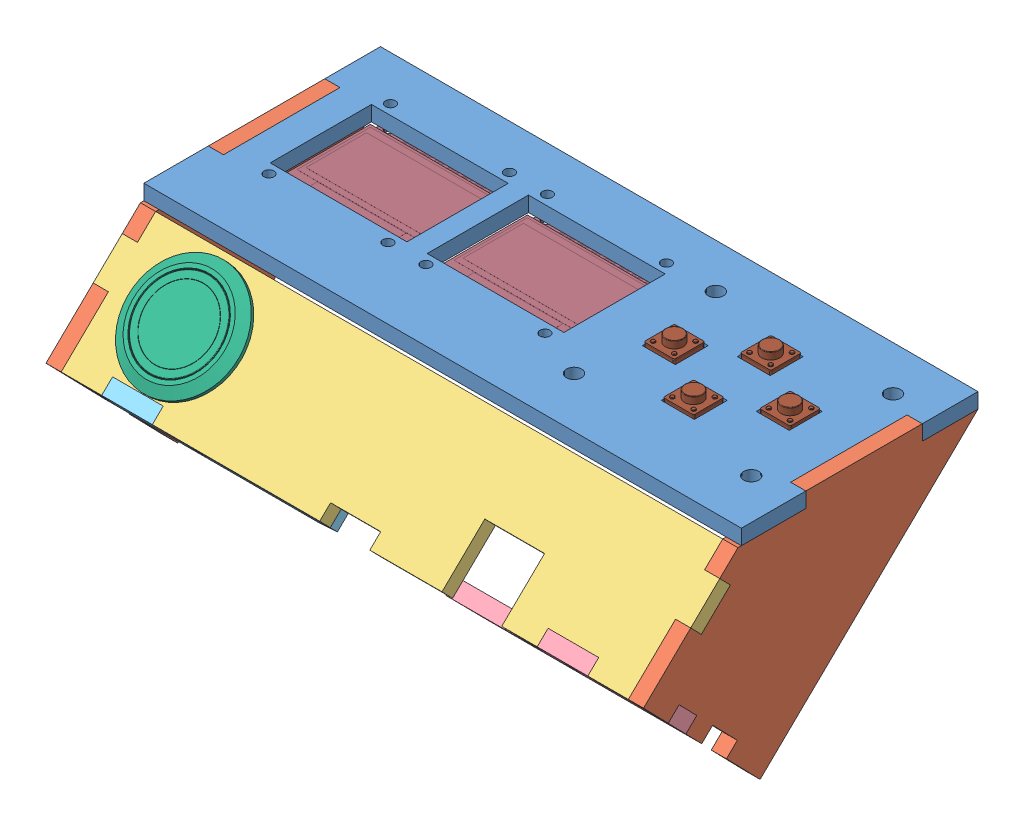
SolidWorks assembly screen, configuration Default. Lengths in mm.
Overall size (118 69.49 69.53).
64 component instances, 18 part files, 28 mates.
Components (placement in the parent):
- screen_face-1: screen_face [Default] at (-28.2935 6.7391 9.7495) size (118 3 46.73)
- screen_side-1: screen_side [Default] at (31.1583 3998.6355 -1824.0898) x (0 -0.717159 -0.69691) z (0 -0.69691 0.717159) size (33.04 3 60)
- screen_front-1: screen_front [Default] at (-1182.2499 1690.6865 -1707.8702) x (1 0 0) z (0 -0.69691 0.717159) size (118 3 26)
- screen_side-2: screen_side [Default] at (-83.8417 3998.6355 -1824.0898) x (0 -0.717159 -0.69691) z (0 -0.69691 0.717159) size (33.04 3 60)
- screen_bottom_right-1: screen_bottom_right [Default] at (-14.7308 -14.1194 45.2949) x (-1 0 0) z (0 -0.717159 -0.69691) size (47.26 3 16.5)
- screen_bottom_left-1: screen_bottom_left [Default] at (-25.4617 -14.6064 40.6384) x (1 0 0) z (0 -0.717159 -0.69691) size (54.05 3 16.5)
- power_switch-1: power_switch [Défaut] at (-65.8417 -14.1024 25.7899) x (0.866025 -0.348455 0.358579) z (0 0.717159 0.69691) size (22 25.2 38.75)
- pcb_buttons-1: pcb_buttons [Default] at (7.7205 6.7731 4.0037) x (-1 0 0) z (0 -1 0) size (43.5 35.88 10.33)
  - Dip_buttons-1: Dip_buttons [Default] at origin size (43.5 35.88 0.32)
  - Capacitor 0603_buttons-1: Capacitor 0603_buttons [Default] at (-1.2809 -0.2801 0.352) x (0 -1 0) z (-1 0 0) size (1.6 0.86 0.86)
  - Capacitor 0603_buttons-2: Capacitor 0603_buttons [Default] at (-3.1859 -0.2507 0.352) x (0 -1 0) z (-1 0 0) size (1.6 0.86 0.86)
  - Capacitor 0603_buttons-3: Capacitor 0603_buttons [Default] at (1.5918 -0.2507 0.352) x (0 -1 0) z (-1 0 0) size (1.6 0.86 0.86)
  - Capacitor 0603_buttons-4: Capacitor 0603_buttons [Default] at (3.4811 -0.2948 0.352) x (0 -1 0) z (-1 0 0) size (1.6 0.86 0.86)
  - Hole_Hole_buttons-1: Hole_Hole_buttons [Default] at (-17.462 13.97 0.322)
  - Hole_Hole_buttons-2: Hole_Hole_buttons [Default] at (17.462 -13.97 0.322)
  - Hole_Hole_buttons-3: Hole_Hole_buttons [Default] at (17.462 13.97 0.322)
  - Hole_Hole_buttons-4: Hole_Hole_buttons [Default] at (-17.462 -13.97 0.322)
  - S4B-ZR-SM4A-TF_buttons-1: S4B-ZR-SM4A-TF_buttons [Default] at (11.146 7.143 0.322) x (0.707107 0.707107 0) z (0.707107 -0.707107 0) size (9 3.7 6.5)
  - 4xRes_0402_buttons-1: 4xRes_0402_buttons [По умолчанию] at (-6.8859 7.489 0.322) x (0 -1 0) z (-1 0 0) size (2 0.37 1)
  - 4xRes_0402_buttons-2: 4xRes_0402_buttons [По умолчанию] at (-6.8317 -7.7471 0.322) x (0 -1 0) z (-1 0 0) size (2 0.37 1)
  - Tactile switch 6x6x5mm_buttons-1: Tactile switch 6x6x5mm_buttons [Valor predeterminado] at (0 7.62 0) x (1 0 0) z (0 1 0) size (6.03 8.52 7.74)
  - Tactile switch 6x6x5mm_buttons-2: Tactile switch 6x6x5mm_buttons [Valor predeterminado] at (-11.43 0 0) x (0 -1 0) z (1 0 0) size (6.03 8.52 7.74)
  - Tactile switch 6x6x5mm_buttons-3: Tactile switch 6x6x5mm_buttons [Valor predeterminado] at (0 -7.62 0) x (1 0 0) z (0 1 0) size (6.03 8.52 7.74)
  - Tactile switch 6x6x5mm_buttons_CUT-1: Tactile switch 6x6x5mm_buttons_CUT [Valor predeterminado] at (11.43 0 0) x (0 -1 0) z (1 0 0) size (6.03 8.52 7.74)
  - B8B-PH-SM4_buttons-1: B8B-PH-SM4_buttons [Default] at (11.938 -9.982 0.322) x (1 0 0) z (0 -1 0) size (15 5 5.2)
  - Via_Via_buttons-1: Via_Via_buttons [Default] at (4.45 0.635 0.322)
  - Via_Via_buttons-2: Via_Via_buttons [Default] at (-7.366 8.89 0.322)
  - Via_Via_buttons-3: Via_Via_buttons [Default] at (3.43 -2.148 0.322)
  - Via_Via_buttons-4: Via_Via_buttons [Default] at (3.43 6.223 0.322)
  - Via_Via_buttons-5: Via_Via_buttons [Default] at (-9.944 -0.354 0.322)
  - Via_Via_buttons-6: Via_Via_buttons [Default] at (-0.313 -0.354 0.322)
  - Via_Via_buttons-7: Via_Via_buttons [Default] at (0.398 6.223 0.322)
  - Via_Via_buttons-8: Via_Via_buttons [Default] at (-5.377 -1.065 0.322)
  - Via_Via_buttons-9: Via_Via_buttons [Default] at (17.196 -2.25 0.322)
  - Via_Via_buttons-10: Via_Via_buttons [Default] at (1.666 -8.001 0.322)
  - Via_Via_buttons-11: Via_Via_buttons [Default] at (-5.645 6.807 0.322)
- display-1: display [Default] at (-18.4635 -4.217 -13.179) x (1 0 0.00008) z (-0.00008 0.000036 1) size (27.3 3.37 27.3)
  - oled_display-1: oled_display [Default] at (-42.7279 10.3551 15.964) size (27.3 2.57 27.3)
  - Capacitor 0603_motor-1: Capacitor 0603_motor [Default] at (-47.8827 7.6343 13.4548) x (0 0 -1) z (1 0 0) size (1.6 0.86 0.86)
  - Resistor 0603_motor-1: Resistor 0603_motor [Default] at (-45.8966 7.9986 13.4983) x (0 0 -1) z (1 0 0) size (1.6 0.51 0.86)
  - Resistor 0603_motor-2: Resistor 0603_motor [Default] at (-43.8966 7.9986 13.4983) x (0 0 -1) z (1 0 0) size (1.6 0.51 0.86)
  - Capacitor 0603_motor-2: Capacitor 0603_motor [Default] at (-49.8827 7.6343 13.4548) x (0 0 -1) z (1 0 0) size (1.6 0.86 0.86)
  - Capacitor 0603_motor-3: Capacitor 0603_motor [Default] at (-51.8827 7.6343 13.4548) x (0 0 -1) z (1 0 0) size (1.6 0.86 0.86)
  - Capacitor 0603_motor-4: Capacitor 0603_motor [Default] at (-53.8827 7.6343 13.4548) x (0 0 -1) z (1 0 0) size (1.6 0.86 0.86)
  - Capacitor 0603_motor-5: Capacitor 0603_motor [Default] at (-41.8827 7.6343 13.4548) x (0 0 -1) z (1 0 0) size (1.6 0.86 0.86)
  - Capacitor 0603_motor-6: Capacitor 0603_motor [Default] at (-37.8827 7.6343 13.4548) x (0 0 -1) z (1 0 0) size (1.6 0.86 0.86)
  - Resistor 0603_motor-3: Resistor 0603_motor [Default] at (-39.8966 7.9986 13.4983) x (0 0 -1) z (1 0 0) size (1.6 0.51 0.86)
  - Resistor 0603_motor-4: Resistor 0603_motor [Default] at (-35.8966 7.9986 13.4983) x (0 0 -1) z (1 0 0) size (1.6 0.51 0.86)
  - Capacitor 0603_motor-7: Capacitor 0603_motor [Default] at (-33.8827 7.6343 13.4548) x (0 0 -1) z (1 0 0) size (1.6 0.86 0.86)
  - Capacitor 0603_motor-8: Capacitor 0603_motor [Default] at (-31.8827 7.6343 13.4548) x (0 0 -1) z (1 0 0) size (1.6 0.86 0.86)
- display-2: display [Default] at (12.5365 -4.217 -13.179) x (1 0 0.00008) z (-0.00008 0.000036 1) size (27.3 3.37 27.3)
  - oled_display-1: oled_display [Default] at (-42.7279 10.3551 15.964) size (27.3 2.57 27.3)
  - Capacitor 0603_motor-1: Capacitor 0603_motor [Default] at (-47.8827 7.6343 13.4548) x (0 0 -1) z (1 0 0) size (1.6 0.86 0.86)
  - Resistor 0603_motor-1: Resistor 0603_motor [Default] at (-45.8966 7.9986 13.4983) x (0 0 -1) z (1 0 0) size (1.6 0.51 0.86)
  - Resistor 0603_motor-2: Resistor 0603_motor [Default] at (-43.8966 7.9986 13.4983) x (0 0 -1) z (1 0 0) size (1.6 0.51 0.86)
  - Capacitor 0603_motor-2: Capacitor 0603_motor [Default] at (-49.8827 7.6343 13.4548) x (0 0 -1) z (1 0 0) size (1.6 0.86 0.86)
  - Capacitor 0603_motor-3: Capacitor 0603_motor [Default] at (-51.8827 7.6343 13.4548) x (0 0 -1) z (1 0 0) size (1.6 0.86 0.86)
  - Capacitor 0603_motor-4: Capacitor 0603_motor [Default] at (-53.8827 7.6343 13.4548) x (0 0 -1) z (1 0 0) size (1.6 0.86 0.86)
  - Capacitor 0603_motor-5: Capacitor 0603_motor [Default] at (-41.8827 7.6343 13.4548) x (0 0 -1) z (1 0 0) size (1.6 0.86 0.86)
  - Capacitor 0603_motor-6: Capacitor 0603_motor [Default] at (-37.8827 7.6343 13.4548) x (0 0 -1) z (1 0 0) size (1.6 0.86 0.86)
  - Resistor 0603_motor-3: Resistor 0603_motor [Default] at (-39.8966 7.9986 13.4983) x (0 0 -1) z (1 0 0) size (1.6 0.51 0.86)
  - Resistor 0603_motor-4: Resistor 0603_motor [Default] at (-35.8966 7.9986 13.4983) x (0 0 -1) z (1 0 0) size (1.6 0.51 0.86)
  - Capacitor 0603_motor-7: Capacitor 0603_motor [Default] at (-33.8827 7.6343 13.4548) x (0 0 -1) z (1 0 0) size (1.6 0.86 0.86)
  - Capacitor 0603_motor-8: Capacitor 0603_motor [Default] at (-31.8827 7.6343 13.4548) x (0 0 -1) z (1 0 0) size (1.6 0.86 0.86)
Mates (geometry in assembly coordinates):
- Coincident7: coincident anti-aligned: plane of screen_face-1 through (31.1583 9.7391 -7.0991) normal (1 0 0); plane of screen_side-1 through (31.1583 3998.6355 -1824.0898) normal (-1 0 0)
- Coincident8: coincident anti-aligned: plane of screen_face-1 through (31.1583 9.7391 15.9009) normal (0 0 -1); plane of screen_side-1 through (34.1583 6.7391 15.9009) normal (0 0 1)
- Coincident9: coincident aligned: plane of screen_side-1 through (34.1583 -2.3207 38.6333) normal (0 0.717159 0.69691); plane of screen_front-1 through (-1182.2499 1692.838 -1705.7795) normal (0 0.717159 0.69691)
- Coincident10: coincident anti-aligned: plane of screen_side-1 through (31.1583 3998.6355 -1824.0898) normal (-1 0 0); plane of screen_front-1 through (31.1583 6.7391 29.3102) normal (1 0 0)
- Coincident11: coincident aligned: plane of screen_face-1 through (-28.2935 9.7391 9.7495) normal (0 1 0); plane of screen_side-1 through (34.1583 9.7391 15.9009) normal (0 1 0)
- Coincident12: coincident anti-aligned: plane of screen_side-1 through (34.1583 -2.3207 38.6333) normal (0 0.69691 -0.717159); plane of screen_front-1 through (31.1583 -2.3207 38.6333) normal (0 -0.69691 0.717159)
- Coincident13: coincident anti-aligned: plane of screen_face-1 through (-80.8417 9.7391 -7.0991) normal (-1 0 0); plane of screen_side-2 through (-80.8417 3998.6355 -1824.0898) normal (1 0 0)
- Coincident14: coincident aligned: plane of screen_face-1 through (-28.2935 9.7391 9.7495) normal (0 1 0); plane of screen_side-2 through (-80.8417 9.7391 15.9009) normal (0 1 0)
- Coincident15: coincident anti-aligned: plane of screen_face-1 through (-83.8417 9.7391 15.9009) normal (0 0 -1); plane of screen_side-2 through (-80.8417 6.7391 15.9009) normal (0 0 1)
- Coincident16: coincident aligned: plane of screen_front-1 through (-1182.2499 1692.838 -1705.7795) normal (0 0.717159 0.69691); plane of screen_bottom_right-1 through (23.1583 -9.2898 45.8048) normal (0 0.717159 0.69691)
- Coincident17: coincident anti-aligned: plane of screen_front-1 through (13.1583 -11.3806 47.9563) normal (1 0 0); plane of screen_bottom_right-1 through (13.1583 -9.2898 45.8048) normal (-1 0 0)
- Coincident18: coincident anti-aligned: plane of screen_front-1 through (13.1583 -9.2898 45.8048) normal (0 -0.69691 0.717159); plane of screen_bottom_right-1 through (-14.7308 -12.0286 43.1434) normal (0 0.69691 -0.717159)
- Coincident21: coincident aligned: plane of screen_front-1 through (-1182.2499 1692.838 -1705.7795) normal (0 0.717159 0.69691); plane of screen_bottom_left-1 through (-72.8417 -11.3806 47.9563) normal (0 0.717159 0.69691)
- Coincident23: coincident aligned: plane of screen_side-2 through (-83.8417 3998.6355 -1824.0898) normal (-1 0 0); plane of screen_bottom_left-1 through (-83.8417 -16.4007 43.078) normal (-1 0 0)
- Coincident24: coincident anti-aligned: plane of screen_front-1 through (-62.8417 -9.2898 45.8048) normal (0 -0.69691 0.717159); plane of screen_bottom_left-1 through (-25.4617 -14.6064 40.6384) normal (0 0.69691 -0.717159)
- Concentric1: concentric aligned: cylinder of screen_front-1 through (-65.8417 -1.6238 37.9161) axis (0 -0.717159 -0.69691) radius 8; cylinder of power_switch-1 through (-65.8417 0.1691 39.6584) axis (0 -0.717159 -0.69691) radius 8.8
- Coincident25: coincident anti-aligned: plane of screen_front-1 through (-1182.2499 1692.838 -1705.7795) normal (0 0.717159 0.69691); plane of power_switch-1 through (-65.8417 -1.6238 37.9161) normal (0 -0.717159 -0.69691)
- Coincident26: coincident anti-aligned: plane of screen_bottom_left-1 through (-25.4617 -14.6064 40.6384) normal (0 0.69691 -0.717159); plane of power_switch-1 through (-72.1926 -10.7242 44.411) normal (0 -0.69691 0.717159)
- Parallel2: parallel anti-aligned: plane of screen_face-1 through (4.4083 9.7391 -6.8198) normal (0 0 1); plane of pcb_buttons-1/Tactile switch 6x6x5mm_buttons-1 through (10.4155 10.3831 -6.6113) normal (0 0 -1)
- Coincident28: coincident anti-aligned: plane of screen_face-1 through (-28.2935 6.7391 9.7495) normal (0 -1 0); plane of pcb_buttons-1/Dip_buttons-1 through (26.0413 6.7391 -10.5052) normal (0 1 0)
- Distance1: distance = 0.3285 mm anti-aligned: plane of pcb_buttons-1/Tactile switch 6x6x5mm_buttons_CUT-1 through (-1.0145 10.3831 1.0087) normal (0 0 -1); plane of screen_face-1 through (-6.8417 9.7391 0.6802) normal (0 0 1)
- Distance2: distance = 0.1372 mm anti-aligned: plane of pcb_buttons-1/Tactile switch 6x6x5mm_buttons_CUT-1 through (-6.7045 10.3831 1.3087) normal (-1 0 0); plane of screen_face-1 through (-6.8417 9.7391 0.6802) normal (1 0 0)
- Concentric2: concentric anti-aligned: cylinder of screen_face-1 through (-73.0917 9.7391 -9.3198) axis (0 -1 0) radius 1; cylinder of display-1/oled_display-1 through (-73.0917 -4.6821 -9.3198) axis (0 1 0) radius 1.025
- Concentric3: concentric anti-aligned: cylinder of screen_face-1 through (-49.5917 9.7391 -9.3198) axis (0 -1 0) radius 1; cylinder of display-1/oled_display-1 through (-49.5917 -4.6821 -9.3198) axis (0 1 0) radius 1.025
- Coincident29: coincident anti-aligned: plane of screen_face-1 through (-28.2935 6.7391 9.7495) normal (0 -1 0); plane of display-1/oled_display-1 through (-61.1927 6.7391 2.7812) normal (0 1 0)
- Concentric4: concentric anti-aligned: cylinder of screen_face-1 through (-42.0917 9.7391 -9.3198) axis (0 -1 0) radius 1; cylinder of display-2/oled_display-1 through (-42.0917 -4.6821 -9.3198) axis (0 1 0) radius 1.025
- Concentric5: concentric anti-aligned: cylinder of screen_face-1 through (-18.5917 9.7391 -9.3198) axis (0 -1 0) radius 1; cylinder of display-2/oled_display-1 through (-18.5917 -4.6821 -9.3198) axis (0 1 0) radius 1.025
- Coincident30: coincident anti-aligned: plane of screen_face-1 through (-28.2935 6.7391 9.7495) normal (0 -1 0); plane of display-2/oled_display-1 through (-30.1927 6.7391 2.7812) normal (0 1 0)
